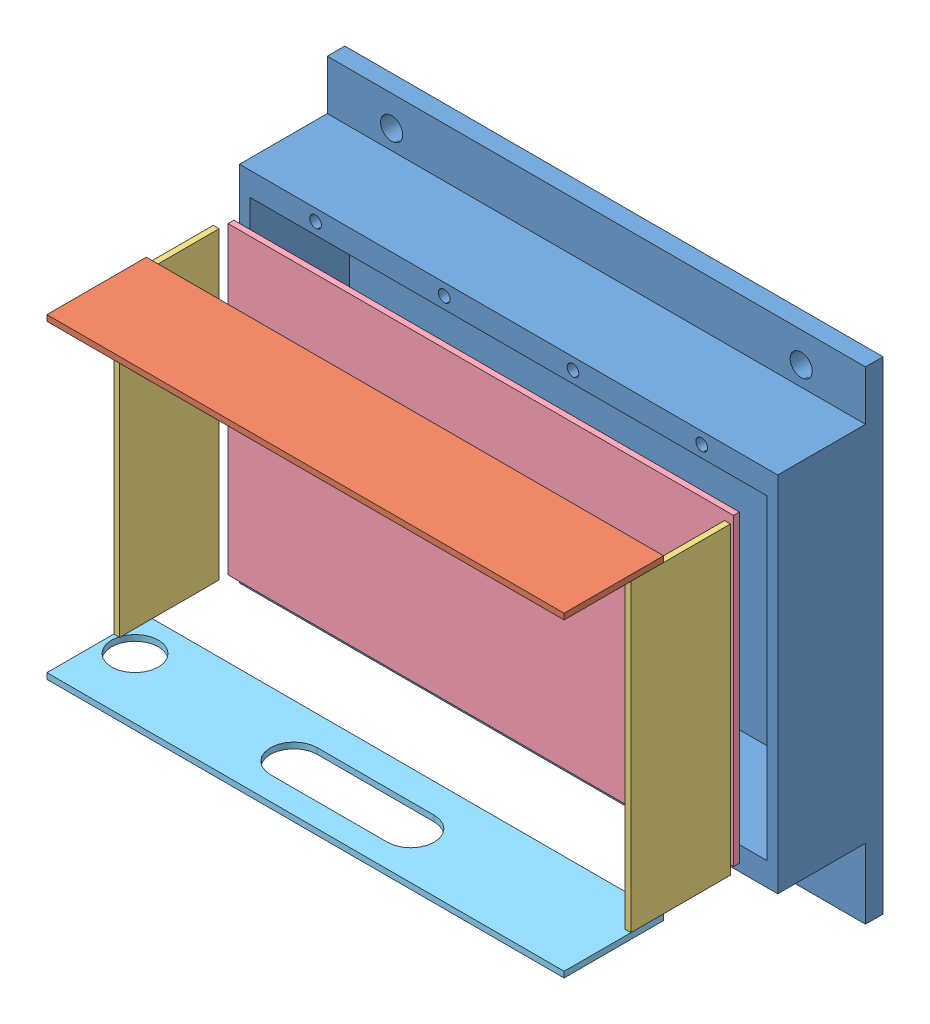
SolidWorks assembly B3_battery - コピー, configuration Default. Lengths in mm.
Overall size (92 82.5 52.71).
14 component instances, 7 part files, 36 mates.
Components (placement in the parent):
- B2_battery_case-1: B2_battery_case [Default] at (-27.6193 12.9444 0.2286) size (92 82.5 18)
- B2_battery_cover-1: B2_battery_cover [Default] at (-73.6193 43.9444 18.2286) size (92 62 1) (hidden)
- B2_battery_insulator1-1: B2_battery_insulator1 [Default] at (-29.6748 38.9444 32.3081) x (1 0 0) z (0 1 0) size (88.4 17 1)
- B2_battery_insulator2-1: B2_battery_insulator2 [Default] at (15.5807 9.9046 25.1332) x (0 -1 0) z (0 0 1) size (52 1 17)
- B2_battery_insulator2-3: B2_battery_insulator2 [Default] at (-71.8193 9.9046 25.1332) x (0 -1 0) z (0 0 1) size (52 1 17)
- B2_battery_insulator3-1: B2_battery_insulator3 [Default] at (-40.702 44.2888 0.2286) x (1 0 0) z (0 -1 0) size (86.4 1 52) (hidden)
- battery-8: battery [Default] at (-149.1297 -13.0556 8.4036) x (-0.702082 0 -0.712097) z (0.712097 0 -0.702082) size (14.35 52 14.35) (hidden)
- battery-9: battery [Default] at (-134.7797 -13.0556 8.4036) x (-0.963236 0 -0.268658) z (0.268658 0 -0.963236) size (14.35 52 14.35) (hidden)
- battery-10: battery [Default] at (-120.4297 -13.0556 8.4036) x (-0.96243 0 -0.271529) z (0.271529 0 -0.96243) size (14.35 52 14.35) (hidden)
- battery-11: battery [Default] at (-106.0797 -13.0556 8.4036) x (0.998572 0 0.05343) z (-0.05343 0 0.998572) size (14.35 52 14.35) (hidden)
- battery-12: battery [Default] at (-91.7297 -13.0556 8.4036) x (-0.654063 0 0.75644) z (-0.75644 0 -0.654063) size (14.35 52 14.35) (hidden)
- battery-14: battery [Default] at (-77.3797 -13.0556 8.4036) x (0.87582 0 0.482638) z (-0.482638 0 0.87582) size (14.35 52 14.35) (hidden)
- B2_battery_insulator3-2: B2_battery_insulator3 [Default] at (-40.702 30.9956 20.9885) x (1 0 0) z (0 -1 0) size (86.4 1 52)
- B3_battery_insulator1 - コピー-1: B3_battery_insulator1 - コピー [Default] at (-29.6748 -13.0556 54.5788) x (1 0 0) z (0 -1 0) size (88.4 17 1)
Mates (geometry in assembly coordinates):
- Coincident46: coincident anti-aligned: plane of ? through (-25.5639 -13.0556 19.864) normal (0 1 0); plane of battery-14 through (8.4057 -13.0556 8.4036) normal (0 -1 0)
- Coincident47: coincident anti-aligned: plane of ? through (-25.5639 -13.0556 19.864) normal (0 1 0); plane of battery-12 through (-5.9443 -13.0556 8.4036) normal (0 -1 0)
- Tangent32: tangent anti-aligned: cylinder of battery-12 through (-91.7297 37.9444 8.4036) axis (0 -1 0) radius 7.175; cylinder of battery-14 through (-77.3797 37.9444 8.4036) axis (0 -1 0) radius 7.175
- Coincident48: coincident anti-aligned: plane of ? through (-25.5639 -13.0556 19.864) normal (0 1 0); plane of battery-11 through (-20.2943 -13.0556 8.4036) normal (0 -1 0)
- Tangent34: tangent anti-aligned: cylinder of battery-11 through (-106.0797 37.9444 8.4036) axis (0 -1 0) radius 7.175; cylinder of battery-12 through (-91.7297 37.9444 8.4036) axis (0 -1 0) radius 7.175
- Coincident49: coincident anti-aligned: plane of ? through (-25.5639 -13.0556 19.864) normal (0 1 0); plane of battery-10 through (-34.6443 -13.0556 8.4036) normal (0 -1 0)
- Tangent36: tangent anti-aligned: cylinder of battery-10 through (-120.4297 37.9444 8.4036) axis (0 -1 0) radius 7.175; cylinder of battery-11 through (-106.0797 37.9444 8.4036) axis (0 -1 0) radius 7.175
- Coincident50: coincident anti-aligned: plane of ? through (-25.5639 -13.0556 19.864) normal (0 1 0); plane of battery-9 through (-48.9943 -13.0556 8.4036) normal (0 -1 0)
- Tangent38: tangent anti-aligned: cylinder of battery-9 through (-134.7797 37.9444 8.4036) axis (0 -1 0) radius 7.175; cylinder of battery-10 through (-120.4297 37.9444 8.4036) axis (0 -1 0) radius 7.175
- Coincident51: coincident anti-aligned: plane of ? through (-25.5639 -13.0556 19.864) normal (0 1 0); plane of battery-8 through (-63.3443 -13.0556 8.4036) normal (0 -1 0)
- Tangent40: tangent anti-aligned: cylinder of battery-8 through (-149.1297 37.9444 8.4036) axis (0 -1 0) radius 7.175; cylinder of battery-9 through (-134.7797 37.9444 8.4036) axis (0 -1 0) radius 7.175
- 一致11: coincident anti-aligned: plane of B2_battery_case-1 through (-27.6193 12.9444 0.2286) normal (0 0 1); plane of B2_battery_insulator3-1 through (-40.702 44.2888 0.2286) normal (0 0 -1)
- 正接1: tangent anti-aligned: plane of B2_battery_insulator3-1 through (-40.702 44.2888 1.2286) normal (0 0 1); cylinder of battery-14 through (-77.3797 37.9444 8.4036) axis (0 -1 0) radius 7.175
- 正接4: tangent anti-aligned: plane of B2_battery_insulator3-1 through (-40.702 44.2888 1.2286) normal (0 0 1); cylinder of battery-12 through (-91.7297 37.9444 8.4036) axis (0 -1 0) radius 7.175
- 正接6: tangent anti-aligned: plane of B2_battery_insulator3-1 through (-40.702 44.2888 1.2286) normal (0 0 1); cylinder of battery-11 through (-106.0797 37.9444 8.4036) axis (0 -1 0) radius 7.175
- 正接7: tangent anti-aligned: plane of B2_battery_insulator3-1 through (-40.702 44.2888 1.2286) normal (0 0 1); cylinder of battery-10 through (-120.4297 37.9444 8.4036) axis (0 -1 0) radius 7.175
- 正接8: tangent anti-aligned: plane of B2_battery_insulator3-1 through (-40.702 44.2888 1.2286) normal (0 0 1); cylinder of battery-9 through (-134.7797 37.9444 8.4036) axis (0 -1 0) radius 7.175
- 正接9: tangent anti-aligned: plane of B2_battery_insulator3-1 through (-40.702 44.2888 1.2286) normal (0 0 1); cylinder of battery-8 through (-149.1297 37.9444 8.4036) axis (0 -1 0) radius 7.175
- 一致22: coincident anti-aligned: plane of B2_battery_case-1 through (-27.6193 12.9444 0.2286) normal (0 0 1); plane of B2_battery_insulator3-1 through (-40.702 44.2888 0.2286) normal (0 0 -1)
- 一致24: coincident anti-aligned: plane of B2_battery_case-1 through (16.5807 -14.0556 17.2286) normal (0 1 0); plane of ? through (-25.5639 -14.0556 19.864) normal (0 -1 0)
- 一致25: coincident anti-aligned: plane of B2_battery_case-1 through (-27.6193 12.9444 17.2286) normal (0 0 1); plane of B2_battery_cover-1 through (-73.6193 43.9444 17.2286) normal (0 0 -1)
- 一致26: coincident aligned: plane of B2_battery_case-1 through (-73.6193 43.9444 17.2286) normal (-1 0 0); plane of B2_battery_cover-1 through (-73.6193 43.9444 17.2286) normal (-1 0 0)
- 一致27: coincident aligned: plane of B2_battery_case-1 through (18.3807 43.9444 17.2286) normal (0 1 0); plane of B2_battery_cover-1 through (-73.6193 43.9444 17.2286) normal (0 1 0)
- 一致31: coincident anti-aligned: plane of B2_battery_case-1 through (-71.8193 39.9444 17.2286) normal (1 0 0); plane of B2_battery_insulator2-3 through (-71.8193 9.9046 25.1332) normal (-1 0 0)
- 一致33: coincident anti-aligned: plane of B2_battery_case-1 through (16.5807 39.9444 17.2286) normal (0 -1 0); plane of B2_battery_insulator1-1 through (-29.6748 39.9444 32.3081) normal (0 1 0)
- 平行1: parallel anti-aligned: plane of B2_battery_case-1 through (-71.8193 39.9444 17.2286) normal (1 0 0); plane of B2_battery_insulator1-1 through (-71.8193 39.9444 34.9434) normal (-1 0 0)
- 一致36: coincident anti-aligned: plane of B2_battery_case-1 through (-71.8193 39.9444 17.2286) normal (1 0 0); plane of B2_battery_insulator1-1 through (-71.8193 39.9444 34.9434) normal (-1 0 0)
- 一致37: coincident anti-aligned: plane of B2_battery_insulator1-1 through (-29.6748 38.9444 32.3081) normal (0 -1 0); plane of B2_battery_insulator2-3 through (-70.8193 38.9444 23.518) normal (0 1 0)
- 一致38: coincident anti-aligned: plane of B2_battery_case-1 through (16.5807 39.9444 17.2286) normal (-1 0 0); plane of B2_battery_insulator2-1 through (16.5807 9.9046 25.1332) normal (1 0 0)
- 一致39: coincident anti-aligned: plane of B2_battery_case-1 through (16.5807 -14.0556 17.2286) normal (0 1 0); plane of B3_battery_insulator1 - コピー-1 through (-29.6748 -14.0556 54.5788) normal (0 -1 0)
- 一致40: coincident anti-aligned: plane of B2_battery_case-1 through (16.5807 39.9444 17.2286) normal (-1 0 0); plane of B3_battery_insulator1 - コピー-1 through (16.5807 -14.0556 51.9434) normal (1 0 0)
- 一致41: coincident aligned: plane of B2_battery_insulator1-1 through (-71.8193 39.9444 51.9434) normal (0 0 1); plane of B3_battery_insulator1 - コピー-1 through (-71.8193 -14.0556 51.9434) normal (0 0 1)
- 一致42: coincident anti-aligned: plane of B2_battery_insulator2-1 through (16.5807 -13.0556 23.518) normal (0 -1 0); plane of B3_battery_insulator1 - コピー-1 through (-29.6748 -13.0556 54.5788) normal (0 1 0)
- 一致43: coincident aligned: plane of B2_battery_insulator2-1 through (16.5807 38.9444 40.518) normal (0 0 1); plane of B2_battery_insulator2-3 through (-70.8193 38.9444 40.518) normal (0 0 1)
- 一致50: coincident anti-aligned: plane of B2_battery_insulator3-2 through (-70.8193 -13.0556 21.9885) normal (0 -1 0); plane of B3_battery_insulator1 - コピー-1 through (-29.6748 -13.0556 54.5788) normal (0 1 0)
- 一致51: coincident anti-aligned: plane of B2_battery_insulator2-1 through (15.5807 9.9046 25.1332) normal (-1 0 0); plane of B2_battery_insulator3-2 through (15.5807 38.9444 21.9885) normal (1 0 0)
